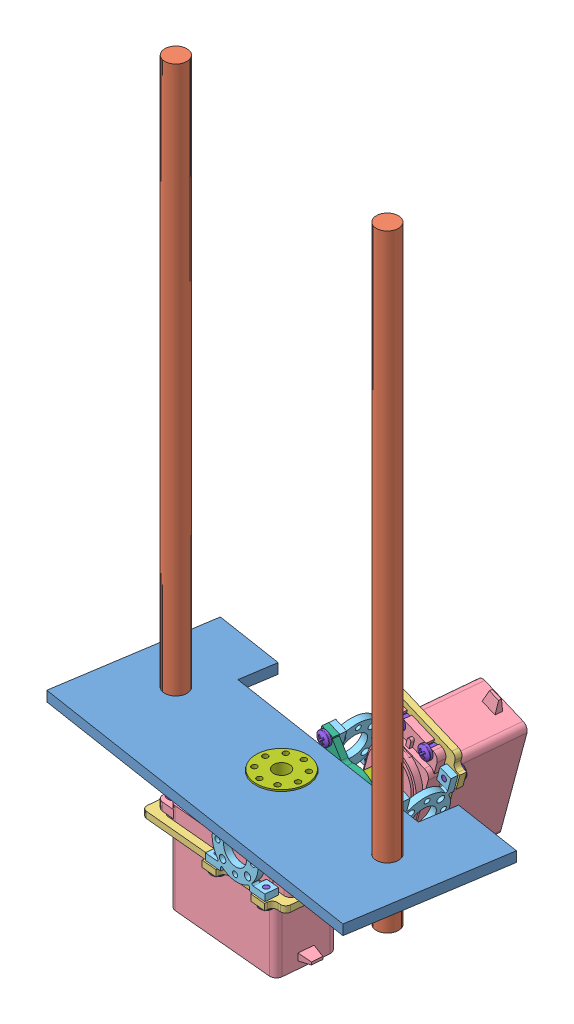
SolidWorks assembly kinectmount_2, configuration Default. Lengths in mm.
Overall size (187.38 359.67 153.6).
41 component instances, 8 part files, 9 mates.
Components (placement in the parent):
- top_plate_support_2-1: top_plate_support_2 [Default] at (32.3217 110.1138 129.0138) x (0.98817 0 0.153364) z (-0.153364 0 0.98817) size (177.8 5.08 76.2)
- hangingrod-1: hangingrod [Default] at (95.0705 237.1138 138.7524) x (0.364647 0 0.931146) z (-0.931146 0 0.364647) size (11.11 304.8 11.11)
- hangingrod-2: hangingrod [Default] at (-30.4271 237.1138 119.2752) x (0.048421 0 0.998827) z (-0.998827 0 0.048421) size (11.11 304.8 11.11)
- 637118-1: 637118 [Default] at (38.1794 89.6201 65.7335) x (-0.956668 0.277416 -0.088472) z (0.276238 0.96075 0.025546) size (46.13 77.81 79.38) (flexible)
  - 575116-1: 575116 [Default] at origin size (44.45 3.17 79.38)
  - Servo HS755-1: Servo HS755 [Default] at (14.2177 -7.7317 -24.4001) x (-1 0 0) z (0 0 -1) size (28.47 55.59 73.84)
  - 545420-1: 545420 [Default] at (-21.463 15.875 0) x (0 -1 0) z (0 0 1) size (25.4 6.35 33.02)
  - 545420-2: 545420 [Default] at (21.463 15.875 0) x (0 1 0) z (0 0 1) size (25.4 6.35 33.02)
  - 535182-1: 535182 [Default] at (0 28.575 -0.0043) size (42.93 5.08 33.3)
  - 525123-1: 525123 [Default] at (0 38.9128 -0.0043) x (0.875516 0 0.48319) z (-0.48319 0 0.875516) size (25.4 25.4 25.4)
  - pan cross head_ai-1: pan cross head_ai [CR-PHMS 0.138-32x0.25x0.25-N] at (-18.288 34.2138 13.4704) x (0 -1 0) z (0.819843 0 0.572588) size (8.77 6.86 6.86)
  - pan cross head_ai-2: pan cross head_ai [CR-PHMS 0.138-32x0.25x0.25-N] at (18.288 34.2138 13.4704) x (0 -1 0) z (0.819843 0 0.572588) size (8.77 6.86 6.86)
  - pan cross head_ai-3: pan cross head_ai [CR-PHMS 0.138-32x0.25x0.25-N] at (18.288 34.2138 -13.479) x (0 -1 0) z (0.819843 0 0.572588) size (8.77 6.86 6.86)
  - pan cross head_ai-4: pan cross head_ai [CR-PHMS 0.138-32x0.25x0.25-N] at (-18.288 34.2138 -13.479) x (0 -1 0) z (0.819843 0 0.572588) size (8.77 6.86 6.86)
  - pan cross head_ai-5: pan cross head_ai [CR-PHMS 0.138-32x0.25x0.25-N] at (-7.9375 9.6393 -49.7649) x (0 -1 0) z (0.819843 0 0.572588) size (8.77 6.86 6.86)
  - pan cross head_ai-6: pan cross head_ai [CR-PHMS 0.138-32x0.25x0.25-N] at (7.8994 9.6393 -49.7649) x (0 -1 0) z (0.819843 0 0.572588) size (8.77 6.86 6.86)
  - pan cross head_ai-7: pan cross head_ai [CR-PHMS 0.138-32x0.25x0.25-N] at (-7.9375 9.6393 18.2563) x (0 -1 0) z (0.819843 0 0.572588) size (8.77 6.86 6.86)
  - pan cross head_ai-8: pan cross head_ai [CR-PHMS 0.138-32x0.25x0.25-N] at (7.8994 9.6393 18.2563) x (0 -1 0) z (0.819843 0 0.572588) size (8.77 6.86 6.86)
  - pan cross head_ai-9: pan cross head_ai [CR-PHMS 0.138-32x0.25x0.25-N] at (-18.288 -2.4638 -13.4704) x (0 1 0) z (0.819843 0 0.572588) size (8.77 6.86 6.86)
  - pan cross head_ai-10: pan cross head_ai [CR-PHMS 0.138-32x0.25x0.25-N] at (-18.288 -2.4638 13.4704) x (0 1 0) z (0.819843 0 0.572588) size (8.77 6.86 6.86)
  - pan cross head_ai-11: pan cross head_ai [CR-PHMS 0.138-32x0.25x0.25-N] at (18.288 -2.4638 -13.4704) x (0 1 0) z (0.819843 0 0.572588) size (8.77 6.86 6.86)
  - pan cross head_ai-12: pan cross head_ai [CR-PHMS 0.138-32x0.25x0.25-N] at (18.288 -2.4638 13.4704) x (0 1 0) z (0.819843 0 0.572588) size (8.77 6.86 6.86)
- 637118-2: 637118 [Default] at (32.326 73.741 129.0142) x (0.092086 0 -0.995751) z (0.995751 0 0.092086) size (46.14 77.81 79.38) (flexible)
  - 575116-1: 575116 [Default] at origin size (44.45 3.17 79.38)
  - Servo HS755-1: Servo HS755 [Default] at (14.2177 -7.7317 -24.4001) x (-1 0 0) z (0 0 -1) size (28.47 55.59 73.84)
  - 545420-1: 545420 [Default] at (-21.463 15.875 0) x (0 -1 0) z (0 0 1) size (25.4 6.35 33.02)
  - 545420-2: 545420 [Default] at (21.463 15.875 0) x (0 1 0) z (0 0 1) size (25.4 6.35 33.02)
  - 535182-1: 535182 [Default] at (0 28.575 -0.0043) size (42.93 5.08 33.3)
  - 525123-1: 525123 [Default] at (0 38.9128 -0.0043) x (0.746883 0 -0.664955) z (0.664955 0 0.746883) size (25.4 25.4 25.4)
  - pan cross head_ai-1: pan cross head_ai [CR-PHMS 0.138-32x0.25x0.25-N] at (-18.288 34.2138 13.4704) x (0 -1 0) z (0.579633 0 0.814877) size (8.77 6.86 6.86)
  - pan cross head_ai-2: pan cross head_ai [CR-PHMS 0.138-32x0.25x0.25-N] at (18.288 34.2138 13.4704) x (0 -1 0) z (0.579633 0 0.814877) size (8.77 6.86 6.86)
  - pan cross head_ai-3: pan cross head_ai [CR-PHMS 0.138-32x0.25x0.25-N] at (18.288 34.2138 -13.479) x (0 -1 0) z (0.579633 0 0.814877) size (8.77 6.86 6.86)
  - pan cross head_ai-4: pan cross head_ai [CR-PHMS 0.138-32x0.25x0.25-N] at (-18.288 34.2138 -13.479) x (0 -1 0) z (0.579633 0 0.814877) size (8.77 6.86 6.86)
  - pan cross head_ai-5: pan cross head_ai [CR-PHMS 0.138-32x0.25x0.25-N] at (-7.9375 9.6393 -49.7649) x (0 -1 0) z (0.579633 0 0.814877) size (8.77 6.86 6.86)
  - pan cross head_ai-6: pan cross head_ai [CR-PHMS 0.138-32x0.25x0.25-N] at (7.8994 9.6393 -49.7649) x (0 -1 0) z (0.579633 0 0.814877) size (8.77 6.86 6.86)
  - pan cross head_ai-7: pan cross head_ai [CR-PHMS 0.138-32x0.25x0.25-N] at (-7.9375 9.6393 18.2563) x (0 -1 0) z (0.579633 0 0.814877) size (8.77 6.86 6.86)
  - pan cross head_ai-8: pan cross head_ai [CR-PHMS 0.138-32x0.25x0.25-N] at (7.8994 9.6393 18.2563) x (0 -1 0) z (0.579633 0 0.814877) size (8.77 6.86 6.86)
  - pan cross head_ai-9: pan cross head_ai [CR-PHMS 0.138-32x0.25x0.25-N] at (-18.288 -2.4638 -13.4704) x (0 1 0) z (0.579633 0 0.814877) size (8.77 6.86 6.86)
  - pan cross head_ai-10: pan cross head_ai [CR-PHMS 0.138-32x0.25x0.25-N] at (-18.288 -2.4638 13.4704) x (0 1 0) z (0.579633 0 0.814877) size (8.77 6.86 6.86)
  - pan cross head_ai-11: pan cross head_ai [CR-PHMS 0.138-32x0.25x0.25-N] at (18.288 -2.4638 -13.4704) x (0 1 0) z (0.579633 0 0.814877) size (8.77 6.86 6.86)
  - pan cross head_ai-12: pan cross head_ai [CR-PHMS 0.138-32x0.25x0.25-N] at (18.288 -2.4638 13.4704) x (0 1 0) z (0.579633 0 0.814877) size (8.77 6.86 6.86)
Mates (geometry in assembly coordinates):
- Concentric1: concentric aligned: cylinder of top_plate_support_2-1 through (-30.4271 115.1938 119.2752) axis (0 -1 0) radius 5.588; cylinder of hangingrod-2 through (-30.4271 389.5138 119.2752) axis (0 -1 0) radius 5.5563
- Concentric2: concentric aligned: cylinder of top_plate_support_2-1 through (95.0705 115.1938 138.7524) axis (0 -1 0) radius 5.588; cylinder of hangingrod-1 through (95.0705 389.5138 138.7524) axis (0 -1 0) radius 5.5563
- Distance1: distance = 25.4 mm aligned: plane of hangingrod-2 through (-30.4271 84.7138 119.2752) normal (0 -1 0); plane of top_plate_support_2-1 through (32.3217 110.1138 129.0138) normal (0 -1 0)
- Distance3: distance = 25.4 mm aligned: plane of hangingrod-1 through (95.0705 84.7138 138.7524) normal (0 -1 0); plane of top_plate_support_2-1 through (32.3217 110.1138 129.0138) normal (0 -1 0)
- Concentric7: concentric aligned: cylinder of 637118-1/525123-1 through (44.0399 89.616 108.5429) axis (-0.092086 0 0.995751) radius 1.3526; cylinder of 637118-2/545420-2 through (43.7475 89.616 111.7044) axis (-0.092086 0 0.995751) radius 1.3526
- Concentric8: concentric aligned: cylinder of 637118-1/525123-1 through (24.565 89.616 106.7419) axis (-0.092086 0 0.995751) radius 1.3526; cylinder of 637118-2/545420-2 through (24.2726 89.616 109.9034) axis (-0.092086 0 0.995751) radius 1.3526
- Coincident7: coincident anti-aligned: plane of 637118-1/525123-1 through (34.3024 89.616 107.6424) normal (-0.092086 0 0.995751); plane of 637118-2/545420-2 through (17.8626 102.316 106.122) normal (0.092086 0 -0.995751)
- Coincident13: coincident anti-aligned: plane of top_plate_support_2-1 through (32.3217 112.6538 129.0138) normal (0 1 0); plane of 637118-2/525123-1 through (32.3217 112.6538 129.0138) normal (0 -1 0)
- Lock1: lock: unknown of top_plate_support_2-1; unknown of 637118-2/525123-1
